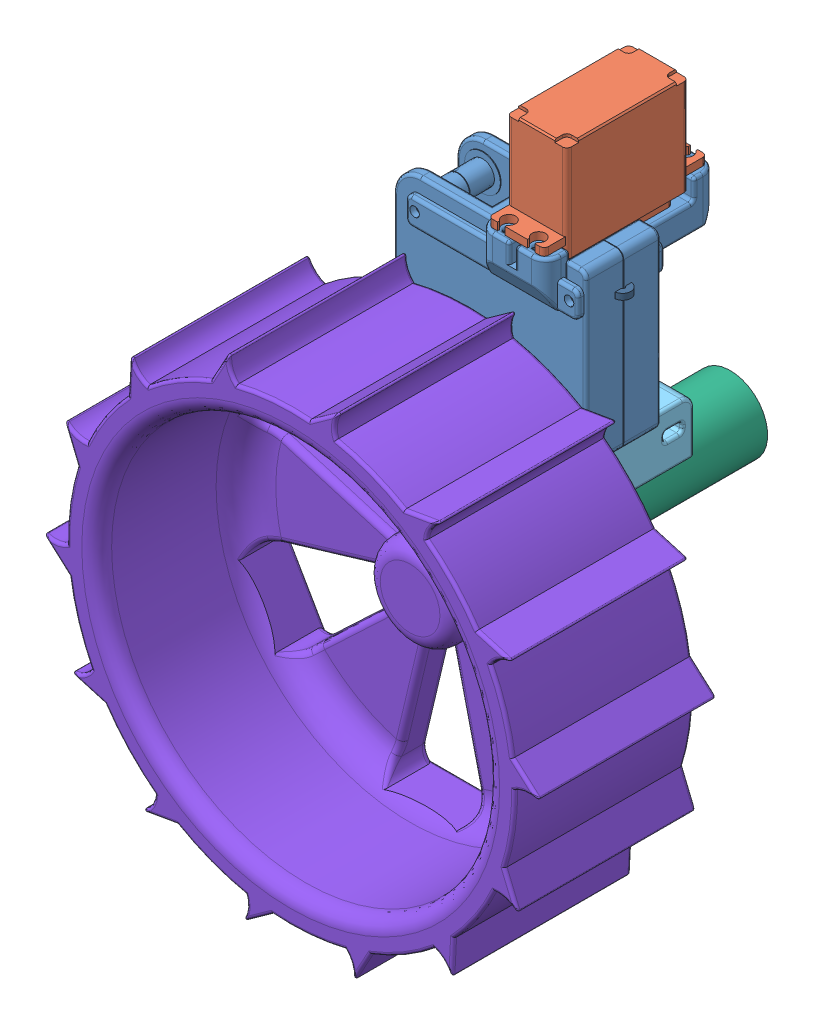
SolidWorks assembly Wheel Hub Subassembly, configuration Right Front. Lengths in mm.
Overall size (165.6 196.56 147.6).
15 component instances, 11 part files, 41 mates.
Components (placement in the parent):
- Upper Wheel Hub-1: Upper Wheel Hub [A] at origin size (64.53 59.8 57.5)
- FeeTech FS5109M Metal Gear Servo Outer volume-1: FeeTech FS5109M Metal Gear Servo Outer volume [Default] at (36.5 60.125 -5.17) x (1 0 0) z (0 0 -1) size (20.1 41.4 54.6)
- 10x15x4mm Bearing-1: 10x15x4mm Bearing [Default] at (36.5 7.025 0) x (1 0 0) z (0 1 0) size (15 15 4)
- 10x15x4mm Bearing-2: 10x15x4mm Bearing [Default] at (36.5 -24.325 0) x (0.876017 0 -0.482279) z (0 1 0) size (15 15 4)
- M10 Hollow Threaded Rod-1: M10 Hollow Threaded Rod [Default] at (36.5 -10.275 0) x (0.010221 0 0.999948) z (-0.999948 0 0.010221) size (10.29 59.32 11.55)
- Wheel Motor Subassembly-1: Wheel Motor Subassembly [Right] at (36.5 -54.975 20) size (165.6 162.92 147.6)
  - Drive Motor Mount-1: Drive Motor Mount [Default] at origin size (25.4 37.4 52.5)
  - BEMONOC 25GA370-1: BEMONOC 25GA370 [Default] at (0 0 -74.8) size (25 25 86.3)
  - Flange Coupling-1: Flange Coupling [Default] at (0 0 12.5) x (1 0 0) z (0 -1 0) size (22 12 22)
  - PaddleWheel-2: PaddleWheel [Right] at (0 0 12.5) x (-1 0 0) z (0 0 -1) size (165.6 162.92 60.59)
- Turning Servo Adapter-1: Turning Servo Adapter [Default] at (36.5 10.625 0) x (-0.242902 0 0.970051) z (-0.970051 0 -0.242902) size (22.51 11.85 44.75)
  - Servo Adapter-1: Servo Adapter [Default] at origin size (15 6.35 15)
  - Servo Horn-1: Servo Horn [Default] at (0 6 0) x (0.970404 0 -0.241488) z (0 1 0) size (12.5 43 5.5)
- Threaded Rod OD Adjustment-1: Threaded Rod OD Adjustment [Default] at (36.5 -29.025 0) x (0.995235 0 -0.097504) z (0.097504 0 0.995235) size (10 6.7 10)
- Threaded Rod OD Adjustment-2: Threaded Rod OD Adjustment [Default] at (36.5 5.025 0) x (0.838679 0 -0.544626) z (0.544626 0 0.838679) size (10 6.7 10)
Mates (geometry in assembly coordinates):
- Coincident1: coordinate: point of Upper Wheel Hub-1
- Concentric1: concentric aligned: cylinder of Upper Wheel Hub-1 through (36.5 -29.025 0) axis (0 1 0) radius 5.5; cylinder of FeeTech FS5109M Metal Gear Servo Outer volume-1 through (36.5 18.725 0) axis (0 1 0) radius 2.85
- Parallel1: parallel anti-aligned: plane of FeeTech FS5109M Metal Gear Servo Outer volume-1 through (26.45 26.925 -29.25) normal (-1 0 0); plane of Upper Wheel Hub-1 through (24.8 30.775 18.4) normal (1 0 0)
- Coincident3: coincident anti-aligned: plane of Upper Wheel Hub-1 through (0 30.775 0) normal (0 1 0); plane of FeeTech FS5109M Metal Gear Servo Outer volume-1 through (44.35 30.775 15.45) normal (0 -1 0)
- Coincident4: coincident anti-aligned: plane of Upper Wheel Hub-1 through (36.5 9.025 0) normal (0 -1 0); plane of 10x15x4mm Bearing-1 through (36.5 9.025 0) normal (0 1 0)
- Concentric2: concentric anti-aligned: cylinder of Upper Wheel Hub-1 through (36.5 -29.025 0) axis (0 1 0) radius 5.5; cylinder of 10x15x4mm Bearing-1 through (36.5 9.025 0) axis (0 -1 0) radius 5
- Coincident5: coincident anti-aligned: plane of Upper Wheel Hub-1 through (36.5 -22.325 0) normal (0 -1 0); plane of 10x15x4mm Bearing-2 through (36.5 -22.325 0) normal (0 1 0)
- Concentric3: concentric anti-aligned: cylinder of Upper Wheel Hub-1 through (36.5 -29.025 0) axis (0 1 0) radius 5.5; cylinder of 10x15x4mm Bearing-2 through (36.5 -22.325 0) axis (0 -1 0) radius 5
- Concentric4: concentric aligned: cylinder of 10x15x4mm Bearing-2 through (36.5 -22.325 0) axis (0 -1 0) radius 5; cylinder of M10 Hollow Threaded Rod-1 through (36.5 18.725 0) axis (0 -1 0) radius 5
- Coincident6: coincident anti-aligned: plane of FeeTech FS5109M Metal Gear Servo Outer volume-1 through (36.5 18.725 0) normal (0 -1 0); plane of M10 Hollow Threaded Rod-1 through (36.5 18.725 0) normal (0 1 0)
- Concentric5: concentric anti-aligned: cylinder of M10 Hollow Threaded Rod-1 through (36.5 18.725 0) axis (0 -1 0) radius 5; cylinder of Drive Motor Mount-1 through (35.5 -78.7084 0) axis (0 1 0) radius 5.5
- Distance1: distance = 5 mm aligned: plane of Wheel Motor Subassembly-1/Drive Motor Mount-1 through (36.5 -34.275 20) normal (0 -1 0); plane of M10 Hollow Threaded Rod-1 through (36.5 -39.275 0) normal (0 -1 0)
- Concentric6: concentric anti-aligned: cylinder of M10 Hollow Threaded Rod-1 through (36.5 18.725 0) axis (0 -1 0) radius 5; cylinder of Wheel Motor Subassembly-1/Drive Motor Mount-1 through (36.5 -67.675 0) axis (0 1 0) radius 5.5
- Concentric7: concentric aligned: cylinder of 10x15x4mm Bearing-1 through (-36.5 8.9 0) axis (0 -1 0) radius 5; cylinder of M10 Hollow Threaded Rod-1 through (-36.5 18.6 0) axis (0 -1 0) radius 5
- Coincident7: coincident anti-aligned: plane of Upper Wheel Hub-1 through (-36.5 8.9 0) normal (0 -1 0); plane of 10x15x4mm Bearing-1 through (-36.5 8.9 0) normal (0 1 0)
- Coincident8: coincident anti-aligned: plane of Upper Wheel Hub-1 through (-36.5 -22.2 0) normal (0 -1 0); plane of 10x15x4mm Bearing-2 through (-36.5 -22.2 0) normal (0 1 0)
- Concentric8: concentric anti-aligned: cylinder of Upper Wheel Hub-1 through (-41.5 30.65 -35.1) axis (0 -1 0) radius 1.35; cylinder of FeeTech FS5109M Metal Gear Servo Outer volume-1 through (-41.5 30.65 -35.1) axis (0 1 0) radius 2.25
- Concentric9: concentric anti-aligned: cylinder of Upper Wheel Hub-1 through (-31.5 30.65 14.4) axis (0 -1 0) radius 1.35; cylinder of FeeTech FS5109M Metal Gear Servo Outer volume-1 through (-31.5 30.65 14.4) axis (0 1 0) radius 2.25
- Coincident9: coincident anti-aligned: plane of FeeTech FS5109M Metal Gear Servo Outer volume-1 through (-36.5 18.6 0) normal (0 -1 0); plane of M10 Hollow Threaded Rod-1 through (-36.5 18.6 0) normal (0 1 0)
- Concentric10: concentric anti-aligned: cylinder of Upper Wheel Hub-1 through (-36.5 -19.3843 0) axis (0 1 0) radius 10; cylinder of M10 Hollow Threaded Rod-1 through (-36.5 18.6 0) axis (0 -1 0) radius 5
- Coincident10: coincident anti-aligned: plane of Upper Wheel Hub-1 through (0 30.65 0) normal (0 1 0); plane of FeeTech FS5109M Metal Gear Servo Outer volume-1 through (-28.65 30.65 15.45) normal (0 -1 0)
- Parallel2: parallel anti-aligned: plane of Upper Wheel Hub-1 through (0 0 12.5) normal (0 0 1); plane of Wheel Motor Subassembly-1/PaddleWheel-2 through (36.5 -54.975 32.5) normal (0 0 -1)
- Parallel3: parallel anti-aligned: plane of Upper Wheel Hub-1 through (0 0 12.5) normal (0 0 1); plane of Wheel Motor Subassembly-1/PaddleWheel-2 through (36.5 -55.1 32.5) normal (0 0 -1)
- Concentric11: concentric anti-aligned: cylinder of FeeTech FS5109M Metal Gear Servo Outer volume-1 through (36.5 18.725 0) axis (0 1 0) radius 2.85; cylinder of Turning Servo Adapter-1/Servo Horn-1 through (36.5 18.625 0) axis (0 -1 0) radius 2.5
- Coincident11: coincident anti-aligned: plane of FeeTech FS5109M Metal Gear Servo Outer volume-1 through (36.5 22.125 0) normal (0 -1 0); plane of Turning Servo Adapter-1/Servo Horn-1 through (36.5 22.125 0) normal (0 1 0)
- Concentric13: concentric aligned: cylinder of M10 Hollow Threaded Rod-1 through (36.5 18.725 0) axis (0 -1 0) radius 5; cylinder of Threaded Rod OD Adjustment-1 through (36.5 -23.025 0) axis (0 -1 0) radius 5
- Concentric14: concentric aligned: cylinder of M10 Hollow Threaded Rod-1 through (36.5 18.725 0) axis (0 -1 0) radius 5; cylinder of Threaded Rod OD Adjustment-2 through (36.5 11.025 0) axis (0 -1 0) radius 5
- Coincident12: coincident aligned: plane of Upper Wheel Hub-1 through (0 -29.025 12.5) normal (0 -1 0); plane of Threaded Rod OD Adjustment-1 through (36.5 -29.025 0) normal (0 -1 0)
- Coincident13: coincident aligned: plane of 10x15x4mm Bearing-1 through (36.5 5.025 0) normal (0 -1 0); plane of Threaded Rod OD Adjustment-2 through (36.5 5.025 0) normal (0 -1 0)
- Concentric15: concentric: cylinder of FeeTech FS5109M Metal Gear Servo Outer volume-1 through (-36.5 18.6 0) axis (0 1 0) radius 2.85; cylinder of Turning Servo Adapter-1/Servo Horn-1 through (-36.5 18.5 0) axis (0 -1 0) radius 2.5
- Coincident14: coincident anti-aligned: plane of FeeTech FS5109M Metal Gear Servo Outer volume-1 through (-36.5 22 0) normal (0 -1 0); plane of Turning Servo Adapter-1/Servo Horn-1 through (-36.5 22 0) normal (0 1 0)
- Concentric16: concentric aligned: cylinder of M10 Hollow Threaded Rod-1 through (-36.5 18.6 0) axis (0 -1 0) radius 5; cylinder of Threaded Rod OD Adjustment-2 through (-36.5 10.9 0) axis (0 -1 0) radius 5
- Coincident15: coincident aligned: plane of 10x15x4mm Bearing-1 through (-36.5 4.9 0) normal (0 -1 0); plane of Threaded Rod OD Adjustment-2 through (-36.5 4.9 0) normal (0 -1 0)
- Concentric17: concentric aligned: cylinder of M10 Hollow Threaded Rod-1 through (-36.5 18.6 0) axis (0 -1 0) radius 5; cylinder of Threaded Rod OD Adjustment-1 through (-36.5 -22.9 0) axis (0 -1 0) radius 5
- Coincident16: coincident aligned: plane of Upper Wheel Hub-1 through (0 -28.9 12.5) normal (0 -1 0); plane of Threaded Rod OD Adjustment-1 through (-36.5 -28.9 0) normal (0 -1 0)
- Concentric18: concentric aligned: cylinder of M10 Hollow Threaded Rod-1 through (36.5 18.6 0) axis (0 -1 0) radius 5; cylinder of Threaded Rod OD Adjustment-1 through (36.5 -22.9 0) axis (0 -1 0) radius 5
- Concentric19: concentric aligned: cylinder of M10 Hollow Threaded Rod-1 through (36.5 18.6 0) axis (0 -1 0) radius 5; cylinder of Threaded Rod OD Adjustment-2 through (36.5 8.9 0) axis (0 -1 0) radius 5
- Concentric20: concentric anti-aligned: cylinder of FeeTech FS5109M Metal Gear Servo Outer volume-1 through (36.5 18.6 0) axis (0 1 0) radius 2.85; cylinder of Turning Servo Adapter-1/Servo Horn-1 through (36.5 18.5 0) axis (0 -1 0) radius 4.25
- Coincident17: coincident anti-aligned: plane of FeeTech FS5109M Metal Gear Servo Outer volume-1 through (36.5 22 0) normal (0 -1 0); plane of Turning Servo Adapter-1/Servo Horn-1 through (36.5 22 0) normal (0 1 0)
- Coincident18: coincident aligned: plane of 10x15x4mm Bearing-1 through (36.5 2.9 0) normal (0 -1 0); plane of Threaded Rod OD Adjustment-2 through (36.5 2.9 0) normal (0 -1 0)
- Coincident19: coincident aligned: plane of Upper Wheel Hub-1 through (0 -28.9 12.5) normal (0 -1 0); plane of Threaded Rod OD Adjustment-1 through (36.5 -28.9 0) normal (0 -1 0)
